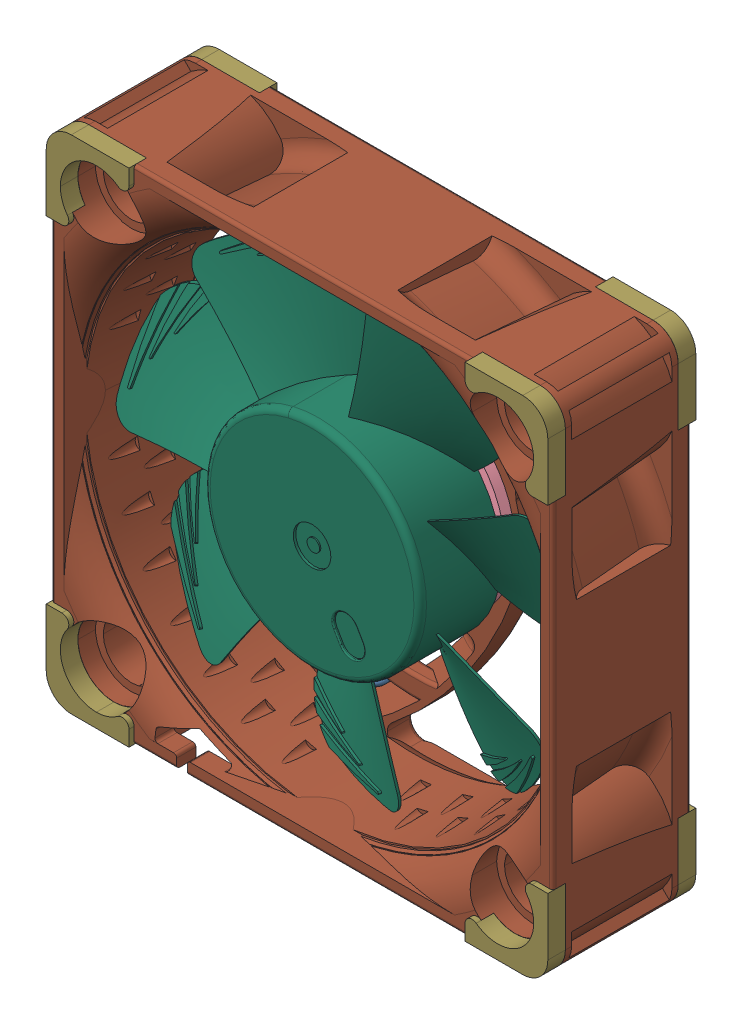
SolidWorks assembly Sestava1, configuration Výchozí. Lengths in mm.
Overall size (43.15 43.24 12.15).
35 component instances, 19 part files, 0 mates.
Components (placement in the parent):
- NF-A4x10 FLX.STEP-1: NF-A4x10 FLX.STEP [Výchozí] at (133.6885 -12.2127 -5.3271) size (43.15 43.24 12.15)
  - Oil Bearing.STEP-1: Oil Bearing.STEP [Výchozí] at (0 0 2) x (1 0 0) z (0 0 -1) size (5 5 5)
    - Bearing.STEP-1: Bearing.STEP [Výchozí] at origin size (5 5 5)
    - Bearing gasket.STEP-1: Bearing gasket.STEP [Výchozí] at (0 0 -1.3) size (2 2 0.5)
    - Oil.STEP-1: Oil.STEP [Výchozí] at (0 0 -4.5) size (4 4 2.7)
    - Bearing gasket.STEP-2: Bearing gasket.STEP [Výchozí] at (0 0 -4.5) size (2 2 0.5)
  - Brushless motor.STEP-1: Brushless motor.STEP [Výchozí] at (0 0 2) size (16 16 8.48)
    - Board.STEP-1: Board.STEP [Výchozí] at origin size (16 16 0.8)
    - Stator.STEP-1: Stator.STEP [Výchozí] at (0 0 3.55) size (11.93 12 5.5)
    - Hall Effect sensor_WE.STEP-1: Hall Effect sensor_WE.STEP [Výchozí] at (-5.3023 -0.9391 0) x (-0.233503 0.972356 0) z (-0.972356 -0.233503 0) size (6.3 1.6 2.6)
    - Controller.STEP-1: Controller.STEP [Výchozí] at (5.1574 2.3195 0) x (0.319288 -0.947658 0) z (0.947658 0.319288 0) size (4.81 0.99 3)
    - Coil.STEP-1: Coil.STEP [Výchozí] at (0 -5.01 1.29) x (-1 0 0) z (0 1 0) size (2.38 5.38 1.58)
    - Coil.STEP-2: Coil.STEP [Výchozí] at (-4.3388 -2.505 1.29) x (-0.5 0.866025 0) z (0.866025 0.5 0) size (2.38 5.38 1.58)
    - Coil.STEP-3: Coil.STEP [Výchozí] at (-4.3388 2.505 1.29) x (0.5 0.866025 0) z (0.866025 -0.5 0) size (2.38 5.38 1.58)
    - Coil.STEP-4: Coil.STEP [Výchozí] at (0 5.01 1.29) x (1 0 0) z (0 -1 0) size (2.38 5.38 1.58)
    - Coil.STEP-5: Coil.STEP [Výchozí] at (4.3388 2.505 1.29) x (0.5 -0.866025 0) z (-0.866025 -0.5 0) size (2.38 5.38 1.58)
    - Coil.STEP-6: Coil.STEP [Výchozí] at (4.3388 -2.505 1.29) x (-0.5 -0.866025 0) z (-0.866025 0.5 0) size (2.38 5.38 1.58)
    - Pieza2^Brushless motor.STEP-1: Pieza2^Brushless motor.STEP [Výchozí] at origin size (10.72 12.51 6.88)
    - Pieza3^Brushless motor.STEP-1: Pieza3^Brushless motor.STEP [Výchozí] at (0 0 0.8) size (4.1 0.74 1.7)
  - Case.STEP-1: Case.STEP [Výchozí] at origin size (41.91 41.91 11.02)
  - Silent block.STEP-1: Silent block.STEP [Výchozí] at (-16 16 10) size (6.6 6.6 1.4)
  - Silent block.STEP-2: Silent block.STEP [Výchozí] at (16 16 10) x (0 -1 0) z (0 0 1) size (6.6 6.6 1.4)
  - Silent block.STEP-3: Silent block.STEP [Výchozí] at (16 -16 10) x (-1 0 0) z (0 0 1) size (6.6 6.6 1.4)
  - Silent block.STEP-4: Silent block.STEP [Výchozí] at (-16 -16 10) x (0 1 0) z (0 0 1) size (6.6 6.6 1.4)
  - Silent block.STEP-5: Silent block.STEP [Výchozí] at (-16 16 -0.4) size (6.6 6.6 1.4)
  - Silent block.STEP-6: Silent block.STEP [Výchozí] at (16 16 -0.4) x (0 -1 0) z (0 0 1) size (6.6 6.6 1.4)
  - Silent block.STEP-7: Silent block.STEP [Výchozí] at (16 -16 -0.4) x (-1 0 0) z (0 0 1) size (6.6 6.6 1.4)
  - Silent block.STEP-8: Silent block.STEP [Výchozí] at (-16 -16 -0.4) x (0 1 0) z (0 0 1) size (6.6 6.6 1.4)
  - Magnet.STEP-1: Magnet.STEP [Výchozí] at (0 0 0.4) size (4.08 4.08 0.9)
  - Back plate.STEP-1: Back plate.STEP [Výchozí] at origin size (15.2 15.2 0.4)
  - Impeller.STEP-1: Impeller.STEP [Výchozí] at (0 0 10.2) x (0.232084 -0.972696 0) z (0 0 1) size (35.91 35.8 6.5)
  - Magnetic screen.STEP-1: Magnetic screen.STEP [Výchozí] at (0 0 3.7) x (0.411264 -0.911516 0) z (0 0 1) size (16.85 16.85 6)
  - Rotor.STEP-1: Rotor.STEP [Výchozí] at (0 0 3.7) x (-0.165519 0.986207 0) z (0 0 -1) size (16.45 16.45 6.1)
  - Shaft.STEP-1: Shaft.STEP [Výchozí] at (0 0 9.8) x (0.165519 -0.986207 0) z (0 0 1) size (2.08 2.08 7.5)
  - Wires^NF-A4x10 FLX.STEP-1: Wires^NF-A4x10 FLX.STEP [Výchozí] at (0 0 2) x (-1 0 0) z (0 0 -1) size (13.5 12.74 7.62)
